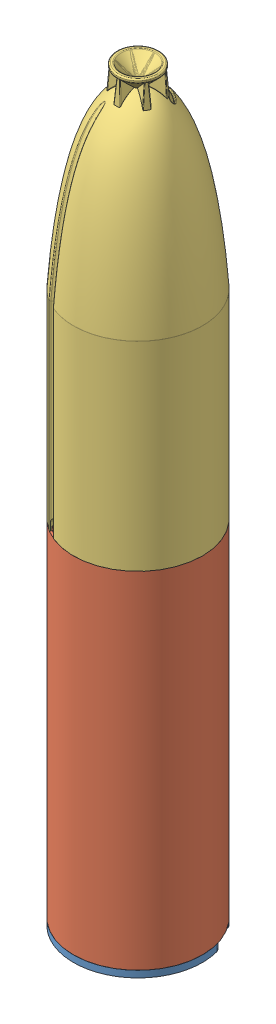
SolidWorks assembly Assem_Parachute_Cups, configuration Default. Lengths in mm.
Overall size (178.91 714.38 187.88).
3 component instances, 3 part files, 4 mates.
Components (placement in the parent):
- PIZZA_v4.0-1: PIZZA_v4.0 [Default] at (-14.2029 -29.9755 24.2398) size (145.61 11.5 126.74)
- Cylinder_Chute_Main^ERS_v3.0-1: Cylinder_Chute_Main^ERS_v3.0 [Default] at (-14.2029 -23.6255 24.2398) x (-0.500912 0 0.865498) z (-0.865498 0 -0.500912) size (139.8 337.75 123.19)
- Cup_Chute_Drogue^ERS_v3.0-1: Cup_Chute_Drogue^ERS_v3.0 [Default] at (-14.2029 306.5745 24.2398) x (0.884997 0 0.465597) z (0 1 0) size (123.19 130.13 378.32)
Mates (geometry in assembly coordinates):
- Concentric1: concentric: circle of PIZZA_v4.0-1; circle of Cylinder_Chute_Main^ERS_v3.0-1
- Parallel1: parallel: line of Cylinder_Chute_Main^ERS_v3.0-1 through (-40.7685 -23.6255 -17.076) axis (-0.500912 0 0.865498); line of PIZZA_v4.0-1 through (-41.5529 -23.6255 -15.2136) axis (-0.500912 0 0.865498)
- Coincident2: coincident: circle of Cylinder_Chute_Main^ERS_v3.0-1; circle of Cup_Chute_Drogue^ERS_v3.0-1
- Coincident3: coincident: plane of PIZZA_v4.0-1 through (-14.2029 -23.6255 24.2398) normal (0 1 0); plane of Cylinder_Chute_Main^ERS_v3.0-1 through (-14.2029 -23.6255 24.2398) normal (0 -1 0)
